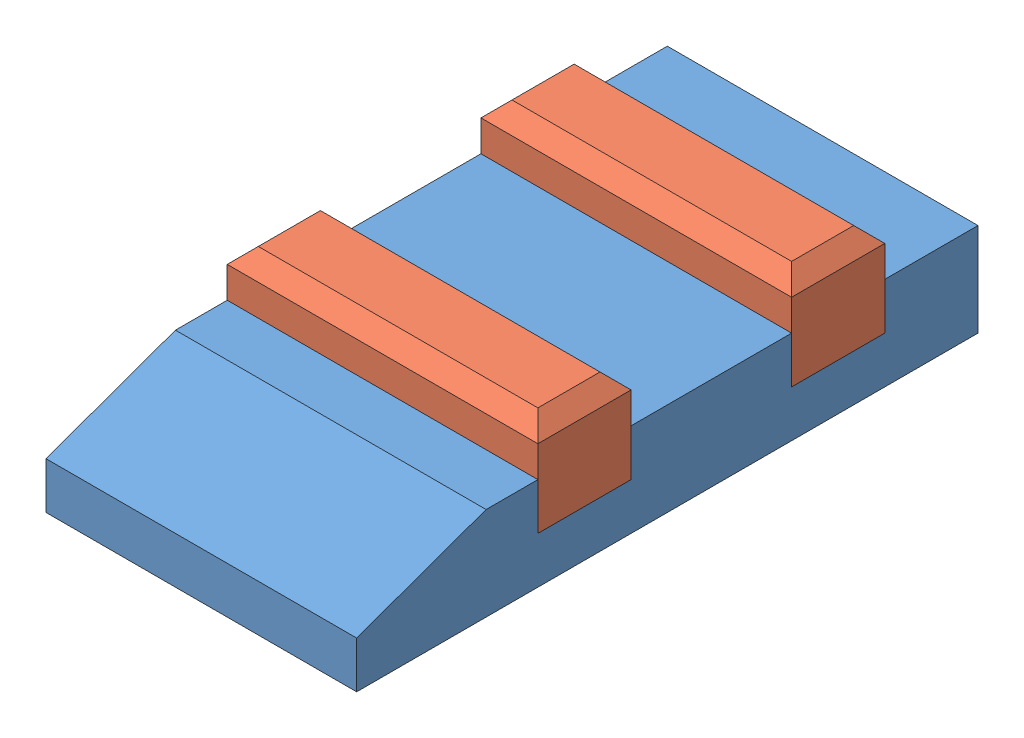
SolidWorks assembly Sanding Pad Assembly, configuration Default. Lengths in mm.
Overall size (60 27 120).
3 component instances, 2 part files, 6 mates.
Components (placement in the parent):
- Body-1: Body [Default] at (42.6831 80.6382 78.4468) size (60 18 120)
- packer piece-1: packer piece [Default] at (102.6831 89.6382 145.4468) x (0 0 -1) z (1 0 0) size (18 18 60)
- packer piece-2: packer piece [Default] at (102.6831 89.6382 96.4468) x (0 0 -1) z (1 0 0) size (18 18 60)
Mates (geometry in assembly coordinates):
- Coincident1: coincident anti-aligned: plane of Body-1 through (42.6831 89.6382 78.4468) normal (0 1 0); plane of packer piece-1 through (102.6831 89.6382 145.4468) normal (0 -1 0)
- Coincident2: coincident aligned: plane of Body-1 through (102.6831 80.6382 78.4468) normal (1 0 0); plane of packer piece-1 through (102.6831 107.6382 145.4468) normal (1 0 0)
- Coincident3: coincident anti-aligned: plane of Body-1 through (42.6831 89.6382 163.4468) normal (0 0 -1); plane of packer piece-1 through (102.6831 107.6382 163.4468) normal (0 0 1)
- Coincident4: coincident anti-aligned: plane of Body-1 through (42.6831 89.6382 78.4468) normal (0 1 0); plane of packer piece-2 through (102.6831 89.6382 96.4468) normal (0 -1 0)
- Coincident5: coincident aligned: plane of Body-1 through (102.6831 80.6382 78.4468) normal (1 0 0); plane of packer piece-2 through (102.6831 107.6382 96.4468) normal (1 0 0)
- Coincident6: coincident anti-aligned: plane of Body-1 through (42.6831 89.6382 114.4468) normal (0 0 -1); plane of packer piece-2 through (102.6831 107.6382 114.4468) normal (0 0 1)
